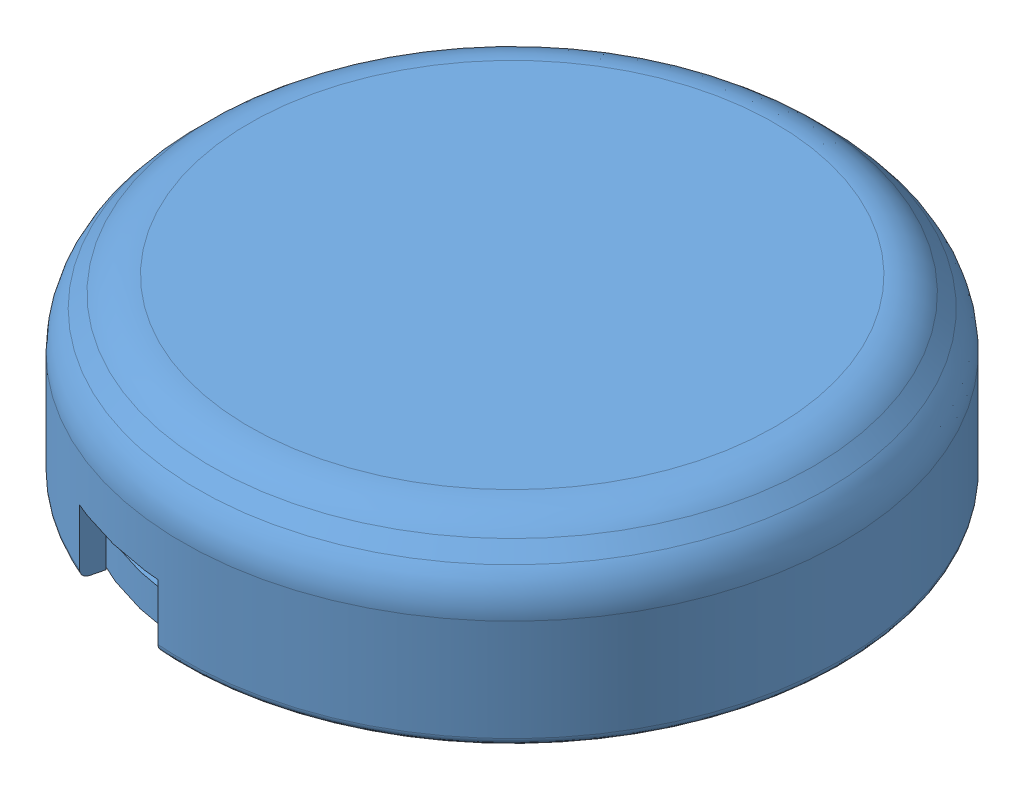
SolidWorks assembly Assembled Biocoin, configuration Default. Lengths in mm.
Overall size (37.88 8.4 37.88).
173 component instances, 44 part files, 7 mates.
Components (placement in the parent):
- Bottom - rev 1-1: Bottom - rev 1 [Default] at (11.776 12.857 23.582) size (30.23 5.59 30.23)
- DPV_PCB_v2.step-1: DPV_PCB_v2.step [Default] at (-1.1972 14.5285 10.4987) x (-0.000274 0 1) z (0 1 0) size (24.9 26.1 3.61)
  - Board.step-1: Board.step [Default] at origin size (24.9 26.1 0.96)
    - Open CASCADE STEP translator 6.8 1.1.1.step-1: Open CASCADE STEP translator 6.8 1.1.1.step [Default] at (0 0 -0.9603) size (24.9 26.1 0.96)
  - R13.step-1: R13.step [Default] at origin size (1.04 0.6 0.34)
    - User_Library-0402R.step-1: User_Library-0402R.step [Default] at (16.3069 1.397 0) x (1 0 0) z (0 -1 0) size (1.04 0.34 0.6)
  - IC4.step-1: IC4.step [Default] at origin size (0.78 0.78 0.38)
    - 6979170656.step-1: 6979170656.step [Default] at (8.3312 18.0086 0) x (-1 0 0) z (0 0 1) size (0.78 0.78 0.38)
      - Array.step-1: Array.step [Default] at origin size (0.66 0.66 0.26)
      - Body.step-1: Body.step [Default] at origin size (0.78 0.78 0.12)
  - R8.step-1: R8.step [Default] at origin size (1.04 0.6 0.34)
    - User_Library-0402R.step-1: User_Library-0402R.step [Default] at (7.3915 11.938 0) x (1 0 0) z (0 -1 0) size (1.04 0.34 0.6)
  - M2.step-1: M2.step [Default] at origin size (15.5 10.5 2.05)
    - MDBT50Q_3D_Drawing_20180620_RGB8421504.step-1: MDBT50Q_3D_Drawing_20180620_RGB8421504.step [Default] at (17.0122 12.9858 0.0128) x (0 -1 0) z (-1 0 0) size (10.5 2.05 15.5)
  - J6.step-1: J6.step [Default] at origin size (2.2 3.46 0.58)
    - 6979173296.step-1: 6979173296.step [Default] at (16.9418 14.4272 -0.9803) x (0 -1 0) z (1 0 0) size (3.46 0.58 2.2)
      - Open CASCADE STEP translator 6.8 1.6.1.1.step-1: Open CASCADE STEP translator 6.8 1.6.1.1.step [Default] at origin size (3.46 0.58 2.2)
      - Open CASCADE STEP translator 6.8 1.6.1.2.step-1: Open CASCADE STEP translator 6.8 1.6.1.2.step [Default] at origin
  - J5.step-1: J5.step [Default] at origin size (2.2 3.46 0.58)
    - 6979183456.step-1: 6979183456.step [Default] at (11.684 14.4272 -0.9803) x (0 1 0) z (-1 0 0) size (3.46 0.58 2.2)
      - Open CASCADE STEP translator 6.8 1.7.1.1.step-1: Open CASCADE STEP translator 6.8 1.7.1.1.step [Default] at origin size (3.46 0.58 2.2)
      - Open CASCADE STEP translator 6.8 1.7.1.2.step-1: Open CASCADE STEP translator 6.8 1.7.1.2.step [Default] at origin
  - L5.step-1: L5.step [Default] at origin size (0.5 1 0.25)
    - SW3dPS-d0402h025.step-1: SW3dPS-d0402h025.step [Default] at (2.4638 7.366 0) x (0 1 0) z (0 0 1) size (1 0.5 0.25)
  - MOSFET1.step-1: MOSFET1.step [Default] at origin size (0.81 0.81 0.39)
    - 6979167456.step-1: 6979167456.step [Default] at (3.8354 7.5946 0) x (0 -1 0) z (0 0 1) size (0.81 0.81 0.39)
  - U5.step-1: U5.step [Default] at origin size (2.1 2 0.55)
    - 6979170736.step-1: 6979170736.step [Default] at (7.3406 16.1036 0) size (2.1 2 0.55)
  - R12.step-1: R12.step [Default] at origin size (1.04 0.6 0.34)
    - User_Library-0402R.step-1: User_Library-0402R.step [Default] at (3.4289 15.3162 0) x (-1 0 0) z (0 1 0) size (1.04 0.34 0.6)
  - IC3.step-1: IC3.step [Default] at origin size (3.1 3 0.8)
    - 6979168976.step-1: 6979168976.step [Default] at (3.4798 17.7292 0) x (-1 0 0) z (0 0 1) size (3.1 3 0.8)
      - Body-0.step-1: Body-0.step [Default] at origin size (3 3 0.75)
      - ThermalPin.step-1: ThermalPin.step [Default] at (-0.825 -1.19 0) size (1.65 2.38 0.1)
      - PinsArrayLR.step-1: PinsArrayLR.step [Default] at origin size (3.1 1.75 0.1)
  - C30.step-1: C30.step [Default] at origin size (0.33 0.64 0.33)
    - 6979172816.step-1: 6979172816.step [Default] at (6.477 18.3388 0) x (0 1 0) z (0 0 1) size (0.64 0.33 0.33)
  - C28.step-1: C28.step [Default] at origin size (0.33 0.64 0.33)
    - 6979172816.step-1: 6979172816.step [Default] at (7.2898 18.3388 0) x (0 1 0) z (0 0 1) size (0.64 0.33 0.33)
  - U4.step-1: U4.step [Default] at origin size (2.44 2.12 1.11)
    - 6979179136.step-1: 6979179136.step [Default] at (7.366 20.193 0) x (-1 0 0) z (0 0 1) size (2.44 2.12 1.11)
  - R11.step-1: R11.step [Default] at origin size (0.6 1.04 0.34)
    - User_Library-0402R.step-1: User_Library-0402R.step [Default] at (11.2014 20.7519 0) x (0 1 0) z (1 0 0) size (1.04 0.34 0.6)
  - R10.step-1: R10.step [Default] at origin size (0.6 1.04 0.34)
    - User_Library-0402R.step-1: User_Library-0402R.step [Default] at (9.906 20.7519 0) x (0 1 0) z (1 0 0) size (1.04 0.34 0.6)
  - C27.step-1: C27.step [Default] at origin size (0.51 1.05 0.51)
    - User_Library-SMD_Ceramic_Capacitors_0402_(1005)_BB.step-1: User_Library-SMD_Ceramic_Capacitors_0402_(1005)_BB.step [Default] at (12.4928 20.7518 0) x (0 -1 0) z (0 0 1) size (1.05 0.51 0.51)
  - C26.step-1: C26.step [Default] at origin size (0.33 0.64 0.33)
    - 6979169616.step-1: 6979169616.step [Default] at (4.3434 21.717 0) x (0 -1 0) z (0 0 1) size (0.64 0.33 0.33)
  - C25.step-1: C25.step [Default] at origin size (0.33 0.64 0.33)
    - 6979169616.step-1: 6979169616.step [Default] at (12.5984 25.1206 0) x (0 -1 0) z (0 0 1) size (0.64 0.33 0.33)
  - U3.step-1: U3.step [Default] at origin size (2.59 1.09 0.56)
    - 6979170016.step-1: 6979170016.step [Default] at (15.4003 24.6078 0) x (0 -1 0) z (0 0 1) size (1.09 2.59 0.56)
  - R9.step-1: R9.step [Default] at origin size (1.04 0.6 0.34)
    - User_Library-0402R.step-1: User_Library-0402R.step [Default] at (7.3915 13.1826 0) x (1 0 0) z (0 -1 0) size (1.04 0.34 0.6)
  - IC2.step-1: IC2.step [Default] at origin size (0.95 1.49 0.53)
    - 6979176416.step-1: 6979176416.step [Default] at (5.08 12.9794 0) x (-1 0 0) z (0 0 1) size (0.95 1.49 0.53)
      - Array-1.step-1: Array-1.step [Default] at origin size (0.65 1.05 0.25)
      - Body-2.step-1: Body-2.step [Default] at origin size (0.95 1.49 0.28)
  - C24.step-1: C24.step [Default] at origin size (0.64 0.33 0.33)
    - 6979180736.step-1: 6979180736.step [Default] at (7.3914 14.3002 0) x (-1 0 0) z (0 0 1) size (0.64 0.33 0.33)
  - L4.step-1: L4.step [Default] at origin size (0.5 1 0.25)
    - SW3dPS-d0402h025.step-1: SW3dPS-d0402h025.step [Default] at (1.2446 10.1092 0) x (0 1 0) z (0 0 1) size (1 0.5 0.25)
  - C13.step-1: C13.step [Default] at origin size (0.33 0.64 0.33)
    - 6979169616.step-1: 6979169616.step [Default] at (5.08 21.717 0) x (0 -1 0) z (0 0 1) size (0.64 0.33 0.33)
  - U2.step-1: U2.step [Default] at origin size (2.44 2.12 1.11)
    - 6979179136.step-1: 6979179136.step [Default] at (7.366 22.6568 0) x (-1 0 0) z (0 0 1) size (2.44 2.12 1.11)
  - R7.step-1: R7.step [Default] at origin size (0.6 1.04 0.34)
    - User_Library-0402R.step-1: User_Library-0402R.step [Default] at (11.2014 22.9363 0) x (0 1 0) z (1 0 0) size (1.04 0.34 0.6)
  - R5.step-1: R5.step [Default] at origin size (0.6 1.04 0.34)
    - User_Library-0402R.step-1: User_Library-0402R.step [Default] at (9.906 22.9363 0) x (0 1 0) z (1 0 0) size (1.04 0.34 0.6)
  - C12.step-1: C12.step [Default] at origin size (0.51 1.05 0.51)
    - User_Library-SMD_Ceramic_Capacitors_0402_(1005)_BB.step-1: User_Library-SMD_Ceramic_Capacitors_0402_(1005)_BB.step [Default] at (12.4928 22.9362 0) x (0 -1 0) z (0 0 1) size (1.05 0.51 0.51)
  - S2.step-1: S2.step [Default] at origin size (2 2 0.65)
    - PMDPB58UPE,115.step-1: PMDPB58UPE,115.step [Default] at (3.2004 10.0076 0.0128) x (0 1 0) z (1 0 0) size (2 0.65 2)
  - J2.step-1: J2.step [Default] at origin size (1.83 3.81 1)
    - 6983029888.step-1: 6983029888.step [Default] at (14.0716 2.4257 0) size (0.25 0.25 0.25)
      - Extruded.step-1: Extruded.step [Default] at origin size (0.25 0.25 0.25)
    - SDO_SOD-123FL_ONS.step-1: SDO_SOD-123FL_ONS.step [Default] at (13.9447 2.5526 0) x (0 1 0) z (0 0 1) size (3.81 1.83 1)
  - S1.step-1: S1.step [Default] at origin size (1.65 2.5 0.56)
    - 6979182816.step-1: 6979182816.step [Default] at (1.2192 13.3096 0) x (0 -1 0) z (0 0 1) size (2.5 1.65 0.56)
  - D1.step-1: D1.step [Default] at origin size (0.51 0.99 0.51)
    - 6979174176.step-1: 6979174176.step [Default] at (4.191 5.3086 0) x (0 1 0) z (0 0 1) size (0.99 0.51 0.51)
  - R6.step-1: R6.step [Default] at origin size (1.04 0.6 0.34)
    - User_Library-0402R.step-1: User_Library-0402R.step [Default] at (13.6825 6.731 0) x (-1 0 0) z (0 1 0) size (1.04 0.34 0.6)
  - L3.step-1: L3.step [Default] at origin size (2 1.97 1.2)
    - 6979182736.step-1: 6979182736.step [Default] at (10.8458 1.778 0) x (-1 0 0) z (0 0 1) size (2 1.97 1.2)
      - term1.step-1: term1.step [Default] at (-1 -0.8 0) size (0.5 1.6 1.2)
      - term2.step-1: term2.step [Default] at (0.5 -0.8 0) size (0.5 1.6 1.2)
      - Body.step-1: Body.step [Default] at (-0.5 -0.784 0.012) size (0.78 0.78 0.12)
  - IC1.step-1: IC1.step [Default] at origin size (1.77 1.77 0.5)
    - 6979167536.step-1: 6979167536.step [Default] at (10.795 6.223 0) x (0 1 0) z (0 0 1) size (1.77 1.77 0.5)
      - Array-3.step-1: Array-3.step [Default] at origin size (1.47 1.47 0.27)
      - Body-4.step-1: Body-4.step [Default] at origin size (1.77 1.77 0.23)
  - C23.step-1: C23.step [Default] at origin size (1.6 0.8 0.3)
    - SW3dPS-0603_SMD_Capacitor.step-1: SW3dPS-0603_SMD_Capacitor.step [Default] at (6.7429 5.5626 0) x (-1 0 0) z (0 1 0) size (1.6 0.3 0.8)
  - C22.step-1: C22.step [Default] at origin size (1.6 0.8 0.3)
    - SW3dPS-0603_SMD_Capacitor.step-1: SW3dPS-0603_SMD_Capacitor.step [Default] at (6.7565 3.683 0) x (-1 0 0) z (0 1 0) size (1.6 0.3 0.8)
  - C21.step-1: C21.step [Default] at origin size (0.51 1.05 0.51)
    - User_Library-SMD_Ceramic_Capacitors_0402_(1005)_BB.step-1: User_Library-SMD_Ceramic_Capacitors_0402_(1005)_BB.step [Default] at (9.9862 4.0386 0) x (0 1 0) z (0 0 1) size (1.05 0.51 0.51)
  - C20.step-1: C20.step [Default] at origin size (1.05 0.51 0.51)
    - User_Library-SMD_Ceramic_Capacitors_0402_(1005)_BB.step-1: User_Library-SMD_Ceramic_Capacitors_0402_(1005)_BB.step [Default] at (13.6826 5.584 0) size (1.05 0.51 0.51)
  - C19.step-1: C19.step [Default] at origin size (1.05 0.51 0.51)
    - User_Library-SMD_Ceramic_Capacitors_0402_(1005)_BB.step-1: User_Library-SMD_Ceramic_Capacitors_0402_(1005)_BB.step [Default] at (11.7348 4.195 0) x (-1 0 0) z (0 0 1) size (1.05 0.51 0.51)
  - J1.step-1: J1.step [Default] at origin size (4.2 4.3 1.45)
    - 6979183296.step-1: 6979183296.step [Default] at (17.7292 4.699 0) x (1 0 0) z (0 -1 0) size (4.2 1.45 4.3)
  - U1.step-1: U1.step [Default] at origin size (4.19 3.61 0.56)
    - 6979180096.step-1: 6979180096.step [Default] at (15.8088 21.6742 0) size (4.19 3.61 0.56)
  - RTIA1.step-1: RTIA1.step [Default] at origin size (1.04 0.6 0.34)
    - User_Library-0402R.step-1: User_Library-0402R.step [Default] at (19.6151 22.6394 0) x (-1 0 0) z (0 1 0) size (1.04 0.34 0.6)
  - RCAL1.step-1: RCAL1.step [Default] at origin size (0.33 0.64 0.33)
    - 6979169616.step-1: 6979169616.step [Default] at (11.6586 25.019 0) x (0 -1 0) z (0 0 1) size (0.64 0.33 0.33)
  - R4.step-1: R4.step [Default] at origin size (0.6 1.04 0.34)
    - User_Library-0402R.step-1: User_Library-0402R.step [Default] at (5.334 7.7645 0) x (0 1 0) z (1 0 0) size (1.04 0.34 0.6)
  - R3.step-1: R3.step [Default] at origin size (0.6 1.04 0.34)
    - User_Library-0402R.step-1: User_Library-0402R.step [Default] at (22.225 5.5627 0) x (0 1 0) z (1 0 0) size (1.04 0.34 0.6)
  - R2.step-1: R2.step [Default] at origin size (0.6 1.04 0.34)
    - User_Library-0402R.step-1: User_Library-0402R.step [Default] at (21.0312 5.5625 0) x (0 -1 0) z (-1 0 0) size (1.04 0.34 0.6)
  - R1.step-1: R1.step [Default] at origin size (0.6 1.04 0.34)
    - User_Library-0402R.step-1: User_Library-0402R.step [Default] at (5.3086 10.1601 0) x (0 1 0) z (1 0 0) size (1.04 0.34 0.6)
  - L2.step-1: L2.step [Default] at origin size (0.5 1 0.25)
    - SW3dPS-d0402h025.step-1: SW3dPS-d0402h025.step [Default] at (2.8956 13.081 0) x (0 -1 0) z (0 0 1) size (1 0.5 0.25)
  - L1.step-1: L1.step [Default] at origin size (1 0.5 0.25)
    - SW3dPS-d0402h025.step-1: SW3dPS-d0402h025.step [Default] at (4.0132 20.193 0) x (-1 0 0) z (0 0 1) size (1 0.5 0.25)
  - CTIA1.step-1: CTIA1.step [Default] at origin size (1.05 0.51 0.51)
    - User_Library-SMD_Ceramic_Capacitors_0402_(1005)_BB.step-1: User_Library-SMD_Ceramic_Capacitors_0402_(1005)_BB.step [Default] at (19.6152 21.5004 0) x (-1 0 0) z (0 0 1) size (1.05 0.51 0.51)
  - CLPF1.step-1: CLPF1.step [Default] at origin size (0.33 0.64 0.33)
    - 6979172816.step-1: 6979172816.step [Default] at (10.8204 24.9936 0) x (0 1 0) z (0 0 1) size (0.64 0.33 0.33)
  - C18.step-1: C18.step [Default] at origin size (0.51 1.05 0.51)
    - User_Library-SMD_Ceramic_Capacitors_0402_(1005)_BB.step-1: User_Library-SMD_Ceramic_Capacitors_0402_(1005)_BB.step [Default] at (7.8954 7.747 0) x (0 -1 0) z (0 0 1) size (1.05 0.51 0.51)
  - C17.step-1: C17.step [Default] at origin size (0.51 1.05 0.51)
    - User_Library-SMD_Ceramic_Capacitors_0402_(1005)_BB.step-1: User_Library-SMD_Ceramic_Capacitors_0402_(1005)_BB.step [Default] at (6.7524 10.152 0) x (0 -1 0) z (0 0 1) size (1.05 0.51 0.51)
  - C16.step-1: C16.step [Default] at origin size (0.51 1.05 0.51)
    - User_Library-SMD_Ceramic_Capacitors_0402_(1005)_BB.step-1: User_Library-SMD_Ceramic_Capacitors_0402_(1005)_BB.step [Default] at (7.8954 10.152 0) x (0 -1 0) z (0 0 1) size (1.05 0.51 0.51)
  - C15.step-1: C15.step [Default] at origin size (0.51 1.05 0.51)
    - User_Library-SMD_Ceramic_Capacitors_0402_(1005)_BB.step-1: User_Library-SMD_Ceramic_Capacitors_0402_(1005)_BB.step [Default] at (6.6254 7.747 0) x (0 -1 0) z (0 0 1) size (1.05 0.51 0.51)
  - C14.step-1: C14.step [Default] at origin size (0.64 0.33 0.33)
    - 6979180736.step-1: 6979180736.step [Default] at (21.2344 19.0754 0) x (-1 0 0) z (0 0 1) size (0.64 0.33 0.33)
  - C11.step-1: C11.step [Default] at origin size (1.05 0.51 0.51)
    - User_Library-SMD_Ceramic_Capacitors_0402_(1005)_BB.step-1: User_Library-SMD_Ceramic_Capacitors_0402_(1005)_BB.step [Default] at (19.6088 20.2558 0) x (-1 0 0) z (0 0 1) size (1.05 0.51 0.51)
  - C10.step-1: C10.step [Default] at origin size (0.64 0.33 0.33)
    - 6979183216.step-1: 6979183216.step [Default] at (9.398 24.638 0) size (0.64 0.33 0.33)
  - C9.step-1: C9.step [Default] at origin size (0.51 1.05 0.51)
    - User_Library-SMD_Ceramic_Capacitors_0402_(1005)_BB.step-1: User_Library-SMD_Ceramic_Capacitors_0402_(1005)_BB.step [Default] at (21.3146 20.7534 0) x (0 1 0) z (0 0 1) size (1.05 0.51 0.51)
  - C8.step-1: C8.step [Default] at origin size (0.64 0.33 0.33)
    - 6979180736.step-1: 6979180736.step [Default] at (19.05 23.6982 0) x (-1 0 0) z (0 0 1) size (0.64 0.33 0.33)
  - C7.step-1: C7.step [Default] at origin size (0.64 0.33 0.33)
    - 6979180736.step-1: 6979180736.step [Default] at (19.3184 19.0326 0) x (-1 0 0) z (0 0 1) size (0.64 0.33 0.33)
  - C6.step-1: C6.step [Default] at origin size (0.64 0.33 0.33)
    - 6979183216.step-1: 6979183216.step [Default] at (15.7988 19.0246 0) size (0.64 0.33 0.33)
  - C5.step-1: C5.step [Default] at origin size (0.64 0.33 0.33)
    - 6979180736.step-1: 6979180736.step [Default] at (14.351 19.0246 0) x (-1 0 0) z (0 0 1) size (0.64 0.33 0.33)
  - C4.step-1: C4.step [Default] at origin size (0.33 0.64 0.33)
    - 6979172816.step-1: 6979172816.step [Default] at (13.4112 25.1206 0) x (0 1 0) z (0 0 1) size (0.64 0.33 0.33)
  - C3.step-1: C3.step [Default] at origin size (0.64 0.33 0.33)
    - 6979183216.step-1: 6979183216.step [Default] at (12.5476 19.0246 0) size (0.64 0.33 0.33)
  - C2.step-1: C2.step [Default] at origin size (0.64 0.33 0.33)
    - 6979180736.step-1: 6979180736.step [Default] at (11.2014 19.0246 0) x (-1 0 0) z (0 0 1) size (0.64 0.33 0.33)
  - C1.step-1: C1.step [Default] at origin size (0.64 0.33 0.33)
    - 6979180736.step-1: 6979180736.step [Default] at (17.3228 19.0246 0) x (-1 0 0) z (0 0 1) size (0.64 0.33 0.33)
- Battery-1: Battery [Default] at (11.7885 16.6806 23.7195) size (24.5 3.3 24.5)
- Top - rev 1-1: Top - rev 1 [Default] at (11.776 12.857 23.582) x (-0.971151 0 -0.238467) z (0.238467 0 -0.971151) size (31.32 8.4 31.32)
- Iontophoresis_MetalElectrodes.step-1: Iontophoresis_MetalElectrodes.step [Default] at (-1.2868 13.8173 10.6063) x (0.002079 0 0.999998) z (0 1 0) size (18.68 24.13 1.64)
  - Board.step-1: Board.step [Default] at origin size (18.68 24.13 0.96)
    - Open CASCADE STEP translator 7.5 1.1.1.step-1: Open CASCADE STEP translator 7.5 1.1.1.step [Default] at (0 0 -0.9603) size (18.68 24.13 0.96)
  - J1.step-1: J1.step [Default] at origin size (2.6 4.7 0.68)
    - 6313637920.step-1: 6313637920.step [Default] at (16.9418 14.4272 0) x (0 1 0) z (1 0 0) size (4.7 0.68 2.6)
      - Open CASCADE STEP translator 7.5 1.2.1.1.step-1: Open CASCADE STEP translator 7.5 1.2.1.1.step [Default] at origin size (4.7 0.68 2.6)
      - Open CASCADE STEP translator 7.5 1.2.1.2.step-1: Open CASCADE STEP translator 7.5 1.2.1.2.step [Default] at origin
  - J2.step-1: J2.step [Default] at origin size (2.6 4.7 0.68)
    - 6313637760.step-1: 6313637760.step [Default] at (11.684 14.4272 0) x (0 -1 0) z (-1 0 0) size (4.7 0.68 2.6)
      - Open CASCADE STEP translator 7.5 1.3.1.1.step-1: Open CASCADE STEP translator 7.5 1.3.1.1.step [Default] at origin size (4.7 0.68 2.6)
      - Open CASCADE STEP translator 7.5 1.3.1.2.step-1: Open CASCADE STEP translator 7.5 1.3.1.2.step [Default] at origin
Mates (geometry in assembly coordinates):
- Coincident2: coincident anti-aligned: plane of Bottom - rev 1-1 through (11.776 13.5682 23.582) normal (0 1 0); plane of DPV_PCB_v2.step-1/Board.step-1/Open CASCADE STEP translator 6.8 1.1.1.step-1 through (6.3229 13.5682 35.3498) normal (0 -1 0)
- Parallel1: parallel aligned: line of Bottom - rev 1-1 through (6.188 14.381 35.5497) axis (1 0 0); line of DPV_PCB_v2.step-1/Board.step-1/Open CASCADE STEP translator 6.8 1.1.1.step-1 through (6.3229 13.5682 35.3498) axis (1 0 0)
- Concentric1: concentric aligned: circle of Bottom - rev 1-1; circle of DPV_PCB_v2.step-1/Board.step-1/Open CASCADE STEP translator 6.8 1.1.1.step-1
- Coincident4: coincident aligned: plane of Bottom - rev 1-1 through (11.776 12.857 23.582) normal (0 -1 0); plane of Top - rev 1-1 through (11.776 12.857 23.582) normal (0 -1 0)
- Concentric7: concentric aligned: circle of Bottom - rev 1-1; circle of Top - rev 1-1
- Parallel8: parallel anti-aligned: plane of DPV_PCB_v2.step-1/Board.step-1/Open CASCADE STEP translator 6.8 1.1.1.step-1 through (6.3229 13.5682 35.3498) normal (0 -1 0); plane of Iontophoresis_MetalElectrodes.step-1/Board.step-1/Open CASCADE STEP translator 7.5 1.1.1.step-1 through (11.7409 13.8173 22.8345) normal (0 1 0)
- Concentric11: concentric aligned: circle of Bottom - rev 1-1; circle of Iontophoresis_MetalElectrodes.step-1/Board.step-1/Open CASCADE STEP translator 7.5 1.1.1.step-1
